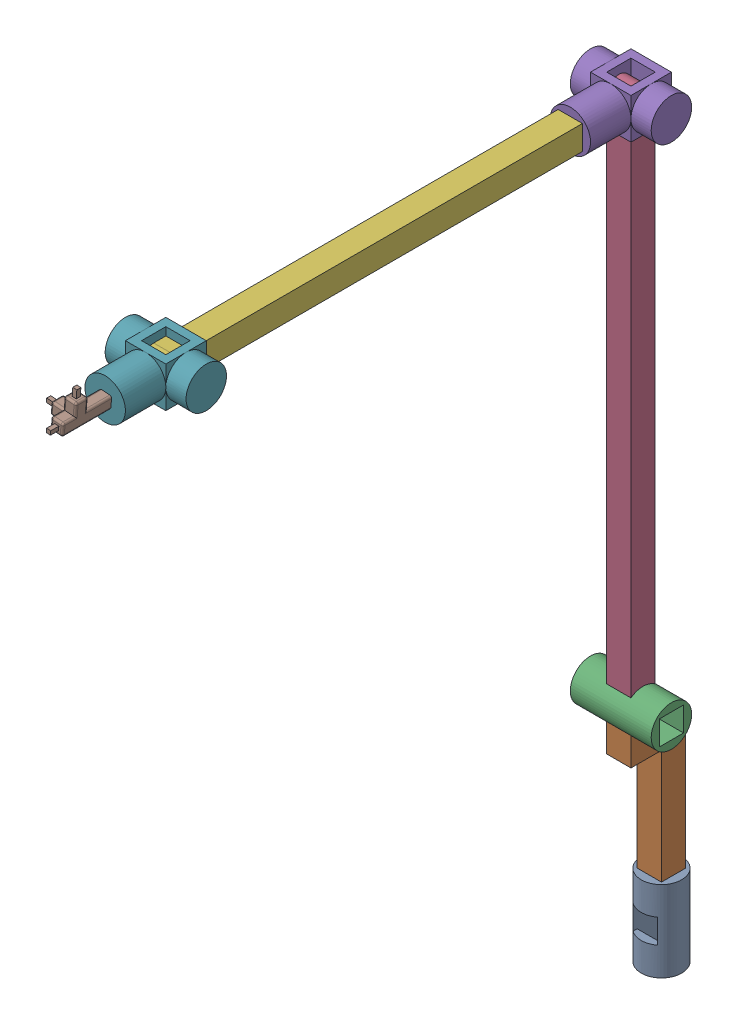
SolidWorks assembly Dummy Assem, configuration Default. Lengths in mm.
Overall size (100 980.9 782.68).
8 component instances, 6 part files, 20 mates.
Components (placement in the parent):
- Joint-1: Joint [Default] at (1.4851 -50.35 33.4234) size (50 100 50)
- Arm1-1: Arm1 [Default] at (1.4851 49.65 33.4234) size (30 181 67.68)
- Joint-2: Joint [Default] at (-48.5149 245.65 71.1073) x (0 0 -1) z (0 -1 0) size (50 100 50)
- Arm2-1: Arm2 [Default] at (1.4851 245.65 71.1073) size (30 680 30)
- Joint T-1: Joint T [Default] at (-48.5149 895.65 71.1073) x (0 -1 0) z (0 0 1) size (50 100 100)
- Arm3-1: Arm3 [Default] at (1.4851 895.65 146.1073) x (0 1 0) z (1 0 0) size (30 515 30)
- Joint T-2: Joint T [Default] at (51.4851 895.65 646.1073) x (0 1 0) z (0 0 1) size (50 100 100)
- End Effector-1: End Effector [Default] at (1.4851 895.65 781.1073) x (0.076696 0.997054 0) z (-0.997054 0.076696 0) size (40 70 40)
Mates (geometry in assembly coordinates):
- Concentric1: concentric anti-aligned: circle of Joint-1; circle of Arm1-1
- Coincident1: coincident anti-aligned: plane of Joint-1 through (1.4851 49.65 33.4234) normal (0 1 0); plane of Arm1-1 through (1.4851 49.65 33.4234) normal (0 -1 0)
- Coincident2: coincident: point of Arm1-1; point of Joint-2
- Coincident3: coincident: point of Arm1-1; point of Joint-2
- Concentric2: concentric anti-aligned: circle of Joint-2; circle of Arm2-1
- Coincident4: coincident anti-aligned: plane of Joint-2 through (16.4851 270.651 86.1073) normal (-1 0 0); plane of Arm2-1 through (16.4851 895.65 56.1073) normal (1 0 0)
- Coincident5: coincident aligned: plane of Arm1-1 through (1.4851 230.65 33.4234) normal (0 1 0); plane of Joint-2 through (-48.5149 230.65 86.1073) normal (0 1 0)
- Concentric3: concentric anti-aligned: circle of Arm2-1; circle of Joint T-1
- Coincident6: coincident anti-aligned: plane of Arm2-1 through (-13.5149 895.65 56.1073) normal (-1 0 0); plane of Joint T-1 through (-12.5525 145.5637 56.5829) normal (1 0 0)
- Concentric6: concentric anti-aligned: circle of Joint T-1; circle of Arm3-1
- Coincident7: coincident anti-aligned: plane of Joint T-1 through (-47.5525 172.2626 146.0939) normal (0 0.018916 0.999821); plane of Arm3-1 through (1.4851 897.0686 146.0939) normal (0 -0.018916 -0.999821)
- Concentric7: concentric anti-aligned: circle of Arm3-1; circle of Joint T-2
- Coincident12: coincident anti-aligned: plane of Arm3-1 through (-13.5149 891.5293 646.2882) normal (-1 0 0); plane of Joint T-2 through (-13.5149 931.5276 631.0044) normal (1 0 0)
- Concentric8: concentric anti-aligned: circle of Joint T-2; circle of End Effector-1
- Coincident15: coincident anti-aligned: plane of Joint T-2 through (51.4851 906.5266 721.0044) normal (0 0 1); plane of End Effector-1 through (1.4851 906.5266 721.0044) normal (0 0 -1)
- Parallel16: parallel aligned: plane of Joint T-1 through (52.4475 170.844 71.1073) normal (1 0 0); plane of Joint T-2 through (51.4851 906.5266 646.0044) normal (1 0 0)
- Parallel17: parallel aligned: plane of Joint-1 through (-13.5149 -50.35 18.4234) normal (0 0 1); plane of Arm1-1 through (-13.5149 220.65 48.4234) normal (0 0 1)
- Parallel18: parallel aligned: plane of Joint-1 through (-13.5149 -50.35 18.4234) normal (0 0 1); plane of Joint T-2 through (51.4851 906.5266 721.0044) normal (0 0 1)
- Parallel20: parallel aligned: plane of Arm1-1 through (-13.5149 220.65 18.4234) normal (0 0 -1); plane of Arm2-1 through (-13.5149 895.65 56.1073) normal (0 0 -1)
- Parallel21: parallel aligned: plane of Arm1-1 through (-13.5149 220.65 18.4234) normal (0 0 -1); plane of Joint T-1 through (51.4851 920.65 46.1073) normal (0 0 -1)
